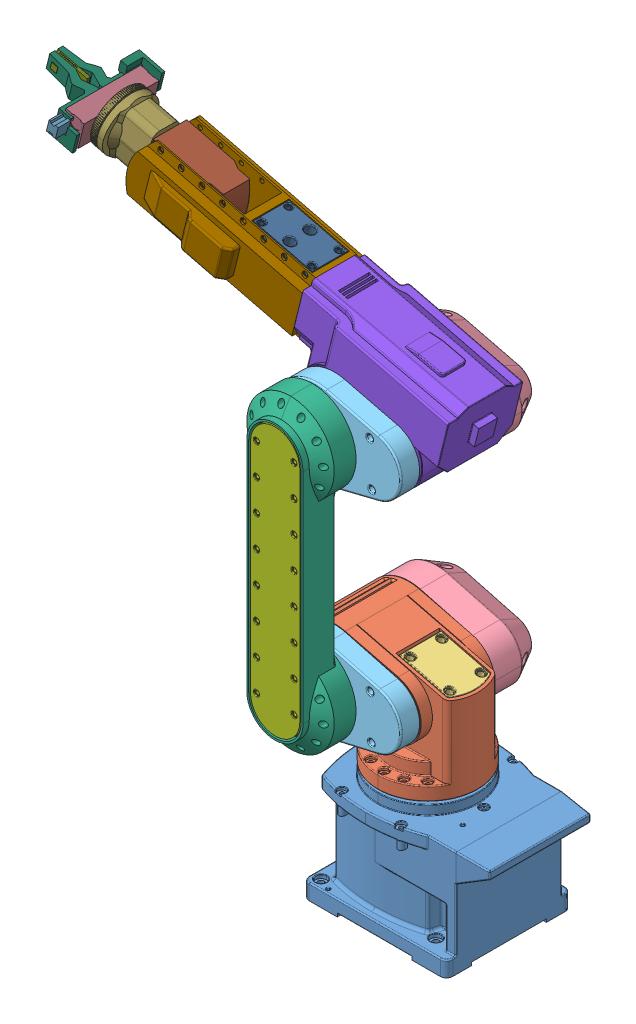
SolidWorks assembly movable step 6, configuration Default. Lengths in mm.
Overall size (786.84 890.65 303.13).
20 component instances, 16 part files, 57 mates.
Components (placement in the parent):
- Base.step-1: Base.step [Default] at (50.4601 21.8888 234.5287) size (280 185 200)
- Joint_1.step-1: Joint_1.step [Default] at (68.2167 333.4398 234.5287) size (242.75 189 160)
- Joint_1_top_cap.step-1: Joint_1_top_cap.step [Default] at (70.5148 316.8888 234.5287) x (1 0 0) z (0 1 0) size (91.2 70 52.34)
- Part3.step-1: Part3.step [Default] at (63.4179 21.928 234.5287) x (0.999815 -0.016322 -0.010154) z (0.010153 -0.000166 0.999948) size (205.53 137 83.39)
- Part4.step-1: Part4.step [Default] at (63.4179 21.928 234.5287) x (0.999815 -0.016322 -0.010154) z (0.010153 -0.000166 0.999948) size (205.37 137 45.97)
- Joint_2.step-1: Joint_2.step [Default] at (-21.7667 647.378 238.6434) x (0 -0.999953 -0.009698) z (0.003009 -0.009698 0.999948) size (490.3 140.11 64.56)
- joint_2_cap.step-1: joint_2_cap.step [Default] at (-275.8903 144.2787 234.5287) x (0.296333 -0.955031 -0.010154) z (0.003009 -0.009698 0.999948) size (415.27 184.72 18.75)
- Part3.step-2: Part3.step [Default] at (68.4534 373.4102 234.5287) x (0.999948 0.000764 -0.010154) z (0.010154 0.000008 0.999948) size (205.53 137 83.39)
- Part4.step-2: Part4.step [Default] at (68.4534 373.4102 234.5287) x (0.999948 0.000764 -0.010154) z (0.010154 0.000008 0.999948) size (205.37 137 45.97)
- Part5.step-1: Part5.step [Default] at (24.1084 630.1919 238.2942) x (0.970756 -0.239852 -0.010154) z (0.009858 -0.002436 0.999948) size (270.42 212 122.27)
- Joint_3_front^industry_robot_arm_3.step-1: Joint_3_front^industry_robot_arm_3.step [Default] at (-224.4166 709.3124 234.7907) x (0.970807 -0.239864 0) z (0 0 1) size (280 99.67 120)
- Joint_3_top_cap^industry_robot_arm_3.step-1: Joint_3_top_cap^industry_robot_arm_3.step [Default] at (295.0467 179.5597 234.7907) x (0.970807 -0.239864 0) z (0 0 1) size (97 20 57)
- joint_4^industry_robot_arm_3.step-1: joint_4^industry_robot_arm_3.step [Default] at (-554.8076 967.2397 234.7907) x (-0.970807 0.239864 0) z (0 0 1) size (126.86 92 60)
- joint_4_front^industry_robot_arm_3.step-1: joint_4_front^industry_robot_arm_3.step [Default] at (-401.6939 796.0726 78.0925) x (0 0 -1) z (0.970807 -0.239864 0) size (88 89.06 70)
- joint_4_super_front^industry_robot_arm_3.step-1: joint_4_super_front^industry_robot_arm_3.step [Default] at (-447.1433 778.8854 -119.2569) x (0 0 1) z (-0.970807 0.239864 0) size (120 40 40)
- joint_4_super_front_middle^industry_robot_arm_3.step-1: joint_4_super_front_middle^industry_robot_arm_3.step [Default] at (-467.3861 778.2523 -180.2963) x (0 0 1) z (-0.970807 0.239864 0) size (160 18 25)
- Gripper_left^industry_robot_arm_3.step-1: Gripper_left^industry_robot_arm_3.step [Default] at (410.0528 507.9058 373.8777) x (0.970807 -0.239864 0) z (0 0 1) size (105.79 39 65)
- Gripper_left^industry_robot_arm_3.step-2: Gripper_left^industry_robot_arm_3.step [Default] at (477.8722 782.3926 90.6237) x (0.970807 -0.239864 0) z (0 0 -1) size (105.79 39 65)
- Gripper_right_grip^industry_robot_arm_3.step-1: Gripper_right_grip^industry_robot_arm_3.step [Default] at (542.6596 1119.0264 2282.2226) x (-0.954279 0.23578 -0.183739) z (-0.178375 0.044072 0.982975) size (52.87 24 20.92)
- Gripper_right_grip^industry_robot_arm_3.step-2: Gripper_right_grip^industry_robot_arm_3.step [Default] at (310.607 179.8353 -1817.7211) x (-0.954279 0.23578 0.183739) z (-0.178375 0.044072 -0.982975) size (52.87 24 20.92)
Mates (geometry in assembly coordinates):
- Concentric1: concentric aligned: cylinder of Base.step-1 through (68.2167 206.8888 234.5287) axis (0 -1 0) radius 80; cylinder of Joint_1.step-1 through (68.2167 222.8888 234.5287) axis (0 -1 0) radius 69
- Coincident1: coincident anti-aligned: plane of Base.step-1 through (68.2167 196.8888 234.5287) normal (0 1 0); plane of Joint_1.step-1 through (68.2167 196.8888 234.5287) normal (0 -1 0)
- Parallel1: parallel aligned: plane of Base.step-1 through (198.2167 111.8888 319.5287) normal (0 0 1); plane of Joint_1.step-1 through (68.2167 333.4398 274.5287) normal (0 0 1)
- Coincident2: coincident anti-aligned: plane of Joint_1.step-1 through (68.2167 316.8888 234.5287) normal (0 1 0); plane of Joint_1_top_cap.step-1 through (70.5148 316.8888 234.5287) normal (0 -1 0)
- Concentric3: concentric aligned: cylinder of Joint_1.step-1 through (68.2167 385.8888 234.5287) axis (0 -1 0) radius 75; cylinder of Joint_1_top_cap.step-1 through (68.2167 470.6805 234.5287) axis (0 -1 0) radius 75.4393
- Parallel2: parallel anti-aligned: plane of Joint_1.step-1 through (52.0118 385.8888 269.5287) normal (1 0 0); plane of Joint_1_top_cap.step-1 through (55.8099 470.6805 201.0287) normal (-1 0 0)
- Coincident3: coincident anti-aligned: plane of Joint_1.step-1 through (68.2167 333.4398 174.5287) normal (0 0 -1); plane of Part3.step-1 through (68.2167 315.8888 174.5287) normal (0 0 1)
- Concentric4: concentric anti-aligned: cylinder of Joint_1.step-1 through (68.2167 315.8888 274.5287) axis (0 0 -1) radius 48.4134; cylinder of Part3.step-1 through (68.2167 315.8888 94.5287) axis (0 0 1) radius 46.9225
- Tangent1: tangent aligned: cylinder of Joint_1.step-1 through (-21.7787 315.8888 274.5287) axis (0 0 -1) radius 70; cylinder of Part3.step-1 through (-21.4511 317.3526 94.5287) axis (0 0 1) radius 68.5
- Coincident4: coincident anti-aligned: plane of Joint_1.step-1 through (68.2167 333.4398 294.5287) normal (0 0 1); plane of Part4.step-1 through (68.2167 315.8888 294.5287) normal (0 0 -1)
- Concentric6: concentric aligned: cylinder of Joint_1.step-1 through (68.2167 315.8888 274.5287) axis (0 0 -1) radius 48.4134; cylinder of Part4.step-1 through (68.2167 315.8888 324.5287) axis (0 0 -1) radius 46.9225
- Tangent2: tangent aligned: cylinder of Joint_1.step-1 through (-21.7787 315.8888 274.5287) axis (0 0 -1) radius 70; cylinder of Part4.step-1 through (-21.4511 317.3526 324.5287) axis (0 0 -1) radius 68.5
- Coincident5: coincident anti-aligned: plane of Part4.step-1 through (-21.7667 317.3577 329.5287) normal (0 0 1); plane of Joint_2.step-1 through (-21.7667 317.3577 329.5287) normal (0 0 -1)
- Concentric7: concentric aligned: cylinder of Part4.step-1 through (-21.7667 317.3577 339.5287) axis (0 0 -1) radius 30; cylinder of Joint_2.step-1 through (-21.7667 317.3577 339.5287) axis (0 0 -1) radius 30
- Parallel3: parallel aligned: plane of Base.step-1 through (198.2167 46.8888 134.5287) normal (1 0 0); plane of Joint_2.step-1 through (23.2333 667.3413 339.5287) normal (1 0 0)
- Concentric8: concentric anti-aligned: cylinder of Joint_2.step-1 through (-21.7667 317.3577 374.5287) axis (0 0 1) radius 42; cylinder of joint_2_cap.step-1 through (-21.7667 317.3577 389.0687) axis (0 0 -1) radius 39.5
- Coincident6: coincident anti-aligned: plane of Joint_2.step-1 through (-21.7667 667.3413 374.5287) normal (0 0 1); plane of joint_2_cap.step-1 through (-21.7667 317.3577 374.5287) normal (0 0 -1)
- Concentric9: concentric anti-aligned: cylinder of Joint_2.step-1 through (-21.7667 667.3413 374.5287) axis (0 0 1) radius 42; cylinder of joint_2_cap.step-1 through (-21.7667 667.3413 389.0687) axis (0 0 -1) radius 39.5
- Coincident7: coincident anti-aligned: plane of Joint_2.step-1 through (-21.7667 667.3413 329.5287) normal (0 0 -1); plane of Part4.step-2 through (-21.7667 667.3413 329.5287) normal (0 0 1)
- Concentric10: concentric aligned: cylinder of Joint_2.step-1 through (-21.7667 667.3413 339.5287) axis (0 0 -1) radius 30; cylinder of Part4.step-2 through (-21.7667 667.3413 339.5287) axis (0 0 -1) radius 30
- Concentric11: concentric anti-aligned: cylinder of Part4.step-2 through (68.2286 667.4101 324.5287) axis (0 0 -1) radius 46.9225; cylinder of Part5.step-1 through (68.2286 667.4101 174.5287) axis (0 0 1) radius 46.9225
- Coincident8: coincident anti-aligned: plane of Part4.step-2 through (68.2286 667.4101 294.5287) normal (0 0 -1); plane of Part5.step-1 through (68.2286 667.4101 294.5287) normal (0 0 1)
- Concentric12: concentric anti-aligned: cylinder of Part4.step-2 through (-21.4511 667.3415 324.5287) axis (0 0 -1) radius 68.5; cylinder of Part5.step-1 through (-21.4511 667.3415 174.5287) axis (0 0 1) radius 68.5
- Coincident9: coincident anti-aligned: plane of Part3.step-2 through (68.2286 667.4101 174.5287) normal (0 0 1); plane of Part5.step-1 through (68.2286 667.4101 174.5287) normal (0 0 -1)
- Concentric13: concentric aligned: cylinder of Part3.step-2 through (-21.4511 667.3415 94.5287) axis (0 0 1) radius 68.5; cylinder of Part5.step-1 through (-21.4511 667.3415 174.5287) axis (0 0 1) radius 68.5
- Tangent3: tangent aligned: cylinder of Part3.step-2 through (68.2286 667.4101 94.5287) axis (0 0 1) radius 46.9225; cylinder of Part5.step-1 through (68.2286 667.4101 174.5287) axis (0 0 1) radius 46.9225
- Parallel4: parallel aligned: plane of Joint_1.step-1 through (75.7423 363.8986 274.5287) normal (0.239864 0.970807 0); plane of Part5.step-1 through (-25.6032 811.0323 179.5287) normal (0.239864 0.970807 0)
- Coincident10: coincident anti-aligned: plane of Part5.step-1 through (-102.9867 727.1449 184.5287) normal (-0.970807 0.239864 0); plane of Joint_3_front^industry_robot_arm_3.step-1 through (-79.0405 824.0629 284.7907) normal (0.970807 -0.239864 0)
- Concentric14: concentric aligned: cylinder of Part5.step-1 through (-100.7016 778.0838 234.5287) axis (0.970807 -0.239864 0) radius 30; cylinder of Joint_3_front^industry_robot_arm_3.step-1 through (-100.7016 778.0838 234.5287) axis (0.970807 -0.239864 0) radius 30
- Distance1: distance = 1.5 mm anti-aligned: plane of Joint_3_top_cap^industry_robot_arm_3.step-1 through (-182.4314 849.6084 206.2907) normal (-0.970807 0.239864 0); plane of Joint_3_front^industry_robot_arm_3.step-1 through (-188.6849 830.5521 204.7907) normal (0.970807 -0.239864 0)
- Distance3: distance = 1.5 mm anti-aligned: plane of Joint_3_top_cap^industry_robot_arm_3.step-1 through (-182.4314 849.6084 263.2907) normal (0 0 1); plane of Joint_3_front^industry_robot_arm_3.step-1 through (-188.6849 830.5521 264.7907) normal (0 0 -1)
- Coincident13: coincident anti-aligned: plane of Joint_3_front^industry_robot_arm_3.step-1 through (-194.1287 831.8972 234.7907) normal (0.239864 0.970807 0); plane of Joint_3_top_cap^industry_robot_arm_3.step-1 through (418.8064 680.455 234.7907) normal (-0.239864 -0.970807 0)
- Parallel5: parallel aligned: plane of Part5.step-1 through (-102.9867 727.1449 284.5287) normal (0 0 1); plane of Joint_3_front^industry_robot_arm_3.step-1 through (-224.4166 709.3124 284.7907) normal (0 0 1)
- Concentric15: concentric anti-aligned: cylinder of Joint_3_front^industry_robot_arm_3.step-1 through (-315.373 832.7636 264.7907) axis (0 0 -1) radius 30; cylinder of joint_4^industry_robot_arm_3.step-1 through (-315.373 832.7636 204.7907) axis (0 0 1) radius 30
- Coincident14: coincident anti-aligned: plane of Joint_3_front^industry_robot_arm_3.step-1 through (-495.1524 824.2125 264.7907) normal (0 0 -1); plane of joint_4^industry_robot_arm_3.step-1 through (-554.8076 967.2397 264.7907) normal (0 0 1)
- Coincident15: coincident anti-aligned: plane of joint_4^industry_robot_arm_3.step-1 through (-346.3749 915.7408 234.7907) normal (-0.970807 0.239864 0); plane of joint_4_front^industry_robot_arm_3.step-1 through (-377.4237 790.076 78.0925) normal (0.970807 -0.239864 0)
- Coincident19: coincident anti-aligned: plane of joint_4^industry_robot_arm_3.step-1 through (-360.3154 859.3189 249.7907) normal (0.239864 0.970807 0); plane of joint_4_front^industry_robot_arm_3.step-1 through (-360.3154 859.3189 249.7907) normal (-0.239864 -0.970807 0)
- Coincident20: coincident anti-aligned: plane of joint_4^industry_robot_arm_3.step-1 through (-367.5113 830.1947 249.7907) normal (0 0 1); plane of joint_4_front^industry_robot_arm_3.step-1 through (-360.3154 859.3189 249.7907) normal (0 0 -1)
- Coincident21: coincident anti-aligned: plane of joint_4_front^industry_robot_arm_3.step-1 through (-430.8181 803.2685 78.0925) normal (-0.970807 0.239864 0); plane of joint_4_super_front^industry_robot_arm_3.step-1 through (-437.4353 776.4867 -119.2569) normal (0.970807 -0.239864 0)
- Coincident22: coincident anti-aligned: plane of joint_4_front^industry_robot_arm_3.step-1 through (-413.7098 872.5114 219.7907) normal (0 0 1); plane of joint_4_super_front^industry_robot_arm_3.step-1 through (-420.9057 843.3872 219.7907) normal (0 0 -1)
- Coincident23: coincident anti-aligned: plane of joint_4_front^industry_robot_arm_3.step-1 through (-413.7098 872.5114 219.7907) normal (-0.239864 -0.970807 0); plane of joint_4_super_front^industry_robot_arm_3.step-1 through (-413.7098 872.5114 249.7907) normal (0.239864 0.970807 0)
- Coincident24: coincident anti-aligned: plane of joint_4_super_front^industry_robot_arm_3.step-1 through (-456.366 781.1641 -119.2569) normal (-0.970807 0.239864 0); plane of joint_4_super_front_middle^industry_robot_arm_3.step-1 through (-457.6781 775.8536 -180.2963) normal (0.970807 -0.239864 0)
- Coincident25: coincident anti-aligned: plane of joint_4_super_front^industry_robot_arm_3.step-1 through (-435.0391 867.4807 239.7907) normal (0 0 -1); plane of joint_4_super_front_middle^industry_robot_arm_3.step-1 through (-435.0391 867.4807 239.7907) normal (0 0 1)
- Coincident26: coincident anti-aligned: plane of joint_4_super_front^industry_robot_arm_3.step-1 through (-435.0391 867.4807 229.7907) normal (-0.239864 -0.970807 0); plane of joint_4_super_front_middle^industry_robot_arm_3.step-1 through (-435.0391 867.4807 239.7907) normal (0.239864 0.970807 0)
- Coincident27: coincident anti-aligned: plane of joint_4_super_front_middle^industry_robot_arm_3.step-1 through (-481.9482 781.8502 -180.2963) normal (-0.970807 0.239864 0); plane of Gripper_left^industry_robot_arm_3.step-1 through (-458.3498 877.3605 294.7907) normal (0.970807 -0.239864 0)
- Coincident28: coincident anti-aligned: plane of joint_4_super_front_middle^industry_robot_arm_3.step-1 through (-458.2395 861.3671 154.7907) normal (-0.239864 -0.970807 0); plane of Gripper_left^industry_robot_arm_3.step-1 through (-458.2395 861.3671 294.7907) normal (0.239864 0.970807 0)
- Parallel6: parallel aligned: plane of Joint_3_top_cap^industry_robot_arm_3.step-1 through (423.6037 699.8711 234.7907) normal (0.239864 0.970807 0); plane of joint_4^industry_robot_arm_3.step-1 through (-228.114 852.4067 264.7907) normal (0.239864 0.970807 0)
- Coincident29: coincident anti-aligned: plane of joint_4_super_front_middle^industry_robot_arm_3.step-1 through (-481.9482 781.8502 -180.2963) normal (-0.970807 0.239864 0); plane of Gripper_left^industry_robot_arm_3.step-2 through (-462.6674 859.886 169.7107) normal (0.970807 -0.239864 0)
- Coincident30: coincident anti-aligned: plane of joint_4_super_front_middle^industry_robot_arm_3.step-1 through (-458.2395 861.3671 154.7907) normal (-0.239864 -0.970807 0); plane of Gripper_left^industry_robot_arm_3.step-2 through (-453.3854 860.1678 169.7107) normal (0.239864 0.970807 0)
- Coincident31: coincident anti-aligned: plane of Gripper_left^industry_robot_arm_3.step-1 through (-501.1855 866.3127 234.7907) normal (0 0 -1); plane of Gripper_right_grip^industry_robot_arm_3.step-1 through (542.6596 1119.0264 234.7907) normal (0 0 1)
- Coincident34: coincident anti-aligned: plane of Gripper_left^industry_robot_arm_3.step-2 through (-495.4288 889.6121 229.7107) normal (0 0 1); plane of Gripper_right_grip^industry_robot_arm_3.step-2 through (310.607 179.8353 229.7107) normal (0 0 -1)
- Coincident35: coincident anti-aligned: plane of Gripper_left^industry_robot_arm_3.step-1 through (-524.1532 889.4987 244.7907) normal (0.970807 -0.239864 0); plane of Gripper_right_grip^industry_robot_arm_3.step-1 through (-526.5518 879.7907 244.7907) normal (-0.970807 0.239864 0)
- Coincident36: coincident anti-aligned: plane of Gripper_left^industry_robot_arm_3.step-1 through (-514.4451 887.1001 244.7907) normal (-0.239864 -0.970807 0); plane of Gripper_right_grip^industry_robot_arm_3.step-1 through (-514.4451 887.1001 244.7907) normal (0.239864 0.970807 0)
- Coincident37: coincident anti-aligned: plane of Gripper_left^industry_robot_arm_3.step-2 through (-516.8438 877.392 219.7107) normal (0.239864 0.970807 0); plane of Gripper_right_grip^industry_robot_arm_3.step-2 through (-516.8438 877.392 219.7107) normal (-0.239864 -0.970807 0)
- Coincident38: coincident anti-aligned: plane of Gripper_left^industry_robot_arm_3.step-2 through (-516.8438 877.392 219.7107) normal (-0.970807 0.239864 0); plane of Gripper_right_grip^industry_robot_arm_3.step-2 through (-514.4451 887.1001 219.7107) normal (0.970807 -0.239864 0)
- Coincident39: coincident anti-aligned: plane of Gripper_right_grip^industry_robot_arm_3.step-1 through (542.6596 1119.0264 232.2507) normal (0 0 -1); plane of Gripper_right_grip^industry_robot_arm_3.step-2 through (310.607 179.8353 232.2507) normal (0 0 1)
- Coincident40: coincident anti-aligned: plane of joint_4_super_front^industry_robot_arm_3.step-1 through (-451.3427 886.96 294.7907) normal (0 0 1); plane of Gripper_left^industry_robot_arm_3.step-1 through (410.0528 507.9058 294.7907) normal (0 0 -1)
